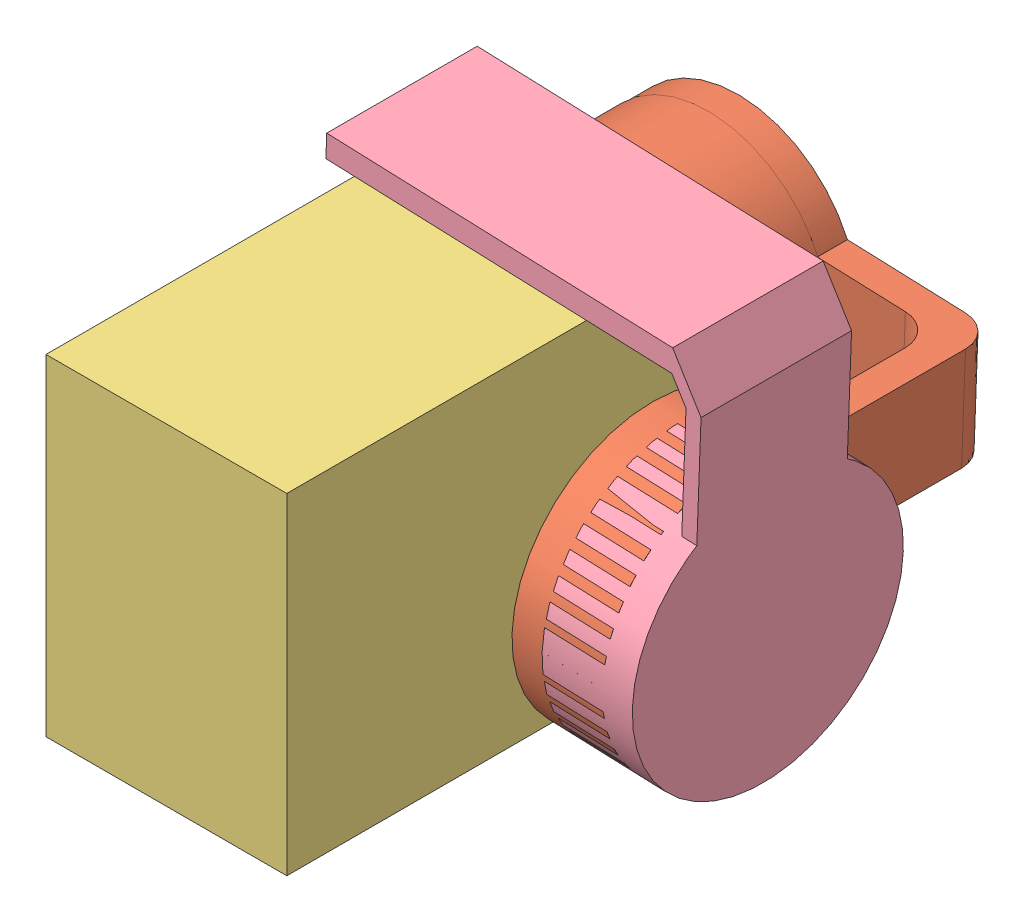
SolidWorks assembly Assem2, configuration Default. Lengths in mm.
Overall size (63.98 62.12 80).
4 component instances, 4 part files, 8 mates.
Components (placement in the parent):
- gimbal part 1-2: gimbal part 1 [Default] at (0 26 -7) size (24 38 70)
- gimbal part 2-1: gimbal part 2 [Default] at (0 26 -7) x (0 0 -1) z (-0.037501 -0.999297 0) size (60 58 36)
- gopro-1: gopro [Default] at (-11.9523 46 7) x (0 0 1) z (0 1 0) size (62 32 44)
- gimbal part 3-1: gimbal part 3 [Default] at (43.9691 24.35 31) x (-0.999297 0.037501 0) z (0 0 -1) size (50 54 36)
Mates (geometry in assembly coordinates):
- Coincident5: coincident: point of gimbal part 1-2
- Coincident10: coincident anti-aligned: plane of gimbal part 1-2 through (0 26 -7) normal (0 0 -1); plane of gimbal part 2-1 through (0 26 -7) normal (0 0 1)
- Concentric1: concentric aligned: cylinder of gimbal part 1-2 through (0 26 3) axis (0 0 -1) radius 12; cylinder of gimbal part 2-1 through (0 26 3) axis (0 0 -1) radius 14
- Coincident12: coincident anti-aligned: plane of gimbal part 1-2 through (-10 2 63) normal (0 1 0); plane of gopro-1 through (20.0477 2 7) normal (0 -1 0)
- Distance1: distance = 4 mm anti-aligned: plane of gopro-1 through (20.0477 46 7) normal (0 0 -1); plane of gimbal part 1-2 through (0 26 3) normal (0 0 1)
- Concentric2: concentric anti-aligned: cylinder of gimbal part 2-1 through (41.9705 24.425 31) axis (-0.999297 0.037501 0) radius 16; cylinder of gimbal part 3-1 through (33.9761 24.725 31) axis (0.999297 -0.037501 0) radius 18
- Coincident13: coincident anti-aligned: plane of gimbal part 2-1 through (33.7136 17.7299 -7) normal (0.999297 -0.037501 0); plane of gimbal part 3-1 through (33.9761 24.725 31) normal (-0.999297 0.037501 0)
- Parallel1: parallel aligned: plane of gopro-1 through (20.0477 46 69) normal (0 0 1); plane of gimbal part 3-1 through (46.5289 39.2311 41) normal (0 0 1)
